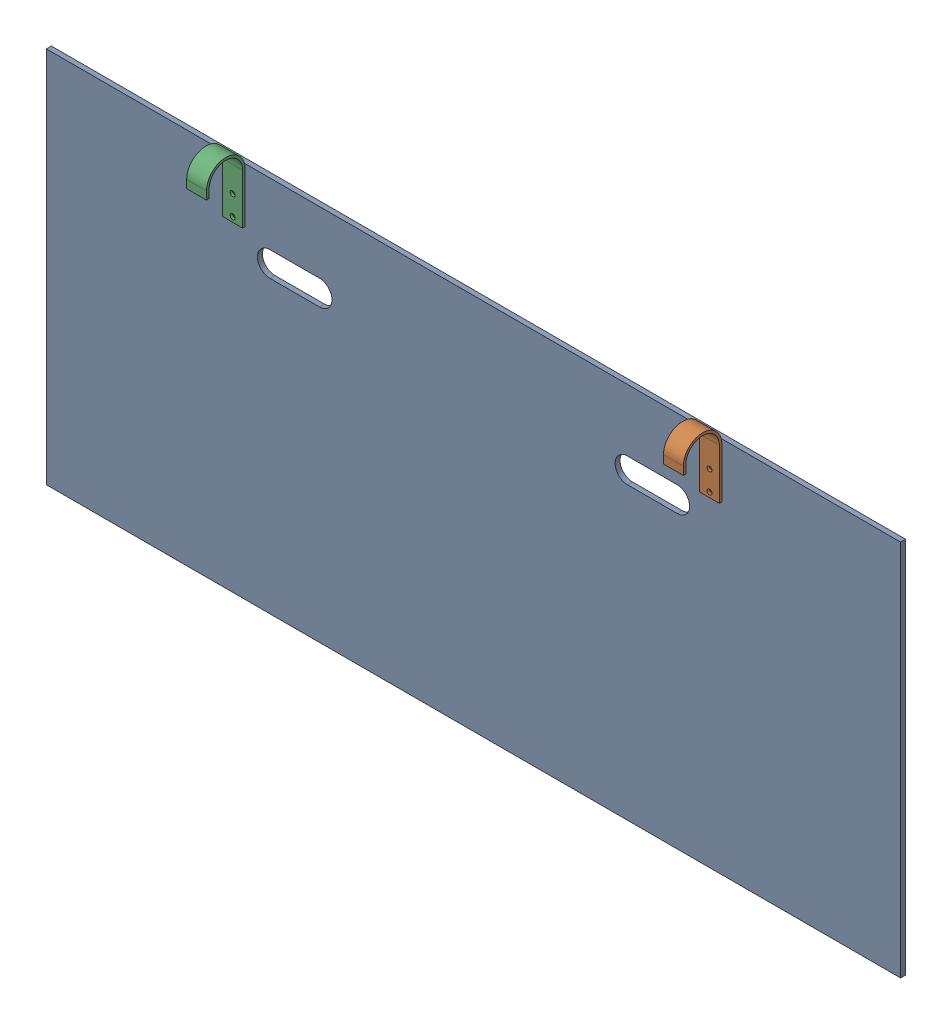
SolidWorks assembly FE-00017_ASM, configuration Default. Lengths in mm.
Overall size (1092.2 501.65 55.56).
3 component instances, 2 part files, 0 mates.
Components (placement in the parent):
- FE-00011-1: FE-00011 [Default] at origin size (1092.2 482.6 6.35)
- FE-00016-1: FE-00016 [Default] at (850.9 412.75 6.35) x (-1 0 0) z (0 -1 0) size (25.4 49.21 88.9)
- FE-00016-2: FE-00016 [Default] at (241.3 412.75 6.35) x (-1 0 0) z (0 -1 0) size (25.4 49.21 88.9)
